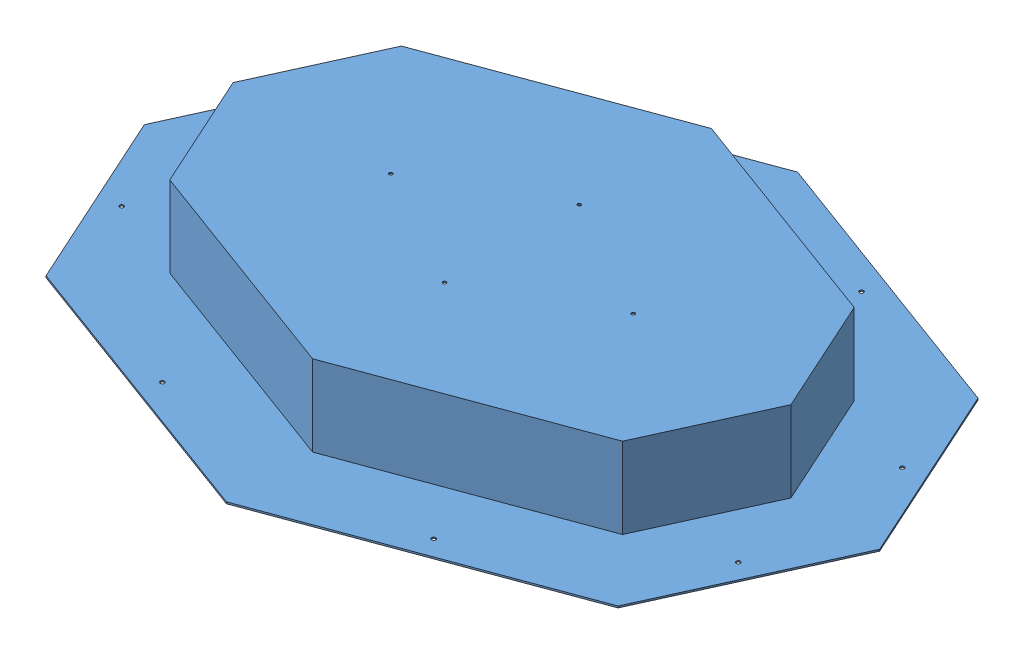
SolidWorks assembly SubAssembly_Lid, configuration Default. Lengths in mm.
Overall size (1707.58 155.58 1071.69).
23 component instances, 6 part files, 46 mates.
Components (placement in the parent):
- HullLid_Octagon-1: HullLid_Octagon [Default] at origin size (1707.58 155.58 1071.69)
- HullFoamTop_Octagon-1: HullFoamTop_Octagon [Default] at origin (suppressed, hidden)
- HullFoamTopPlate_Octagon-2: HullFoamTopPlate_Octagon [Default] at (0 305.9906 0) (suppressed, hidden)
- 90575A223_TYPE 316 STAINLESS STEEL FULLY THREADED STUD-2: 90575A223_TYPE 316 STAINLESS STEEL FULLY THREADED STUD [90575A223] at (-228.6 228.6 0) x (0 1 0) z (0 0 1) (suppressed, hidden)
- 90575A223_TYPE 316 STAINLESS STEEL FULLY THREADED STUD-5: 90575A223_TYPE 316 STAINLESS STEEL FULLY THREADED STUD [90575A223] at (0 228.6 127) x (0 1 0) z (-0.108702 0 -0.994074) (suppressed, hidden)
- 90575A223_TYPE 316 STAINLESS STEEL FULLY THREADED STUD-6: 90575A223_TYPE 316 STAINLESS STEEL FULLY THREADED STUD [90575A223] at (228.6 228.6 0) x (0 1 0) z (0.395734 0 0.918365) (suppressed, hidden)
- 90575A223_TYPE 316 STAINLESS STEEL FULLY THREADED STUD-7: 90575A223_TYPE 316 STAINLESS STEEL FULLY THREADED STUD [90575A223] at (0 228.6 -127) x (0 1 0) z (0.6 0 0.8) (suppressed, hidden)
- 90770A029_ALLOY 20 STAINLESS STEEL FLAT WASHER-1: 90770A029_ALLOY 20 STAINLESS STEEL FLAT WASHER [90770A029] at (-228.6 307.1813 0) x (0 1 0) z (0 0 1) (suppressed, hidden)
- 90770A029_ALLOY 20 STAINLESS STEEL FLAT WASHER-2: 90770A029_ALLOY 20 STAINLESS STEEL FLAT WASHER [90770A029] at (0 307.1813 -127) x (0 1 0) z (0.188455 0 0.982082) (suppressed, hidden)
- 90770A029_ALLOY 20 STAINLESS STEEL FLAT WASHER-3: 90770A029_ALLOY 20 STAINLESS STEEL FLAT WASHER [90770A029] at (228.6 307.1813 0) x (0 1 0) z (0.395734 0 0.918365) (suppressed, hidden)
- 90770A029_ALLOY 20 STAINLESS STEEL FLAT WASHER-4: 90770A029_ALLOY 20 STAINLESS STEEL FLAT WASHER [90770A029] at (0 307.1813 127) x (0 1 0) z (0.6 0 0.8) (suppressed, hidden)
- 90770A029_ALLOY 20 STAINLESS STEEL FLAT WASHER-5: 90770A029_ALLOY 20 STAINLESS STEEL FLAT WASHER [90770A029] at (-228.6 150.0188 0) x (0 -1 0) z (1 0 0) (suppressed, hidden)
- 90770A029_ALLOY 20 STAINLESS STEEL FLAT WASHER-6: 90770A029_ALLOY 20 STAINLESS STEEL FLAT WASHER [90770A029] at (0 150.0188 -127) x (0 -1 0) z (0.982082 0 -0.188455) (suppressed, hidden)
- 90770A029_ALLOY 20 STAINLESS STEEL FLAT WASHER-7: 90770A029_ALLOY 20 STAINLESS STEEL FLAT WASHER [90770A029] at (0 150.0188 127) x (0 -1 0) z (0.918365 0 -0.395734) (suppressed, hidden)
- 90770A029_ALLOY 20 STAINLESS STEEL FLAT WASHER-8: 90770A029_ALLOY 20 STAINLESS STEEL FLAT WASHER [90770A029] at (228.6 150.0188 0) x (0 -1 0) z (0.8 0 -0.6) (suppressed, hidden)
- 94819A043_ASTM F594 TYPE 316 STAINLESS STEEL HEX NUT-15: 94819A043_ASTM F594 TYPE 316 STAINLESS STEEL HEX NUT [94819A043] at (-228.6 311.7374 0) x (1 0 0) z (0 -1 0) (suppressed, hidden)
- 94819A043_ASTM F594 TYPE 316 STAINLESS STEEL HEX NUT-16: 94819A043_ASTM F594 TYPE 316 STAINLESS STEEL HEX NUT [94819A043] at (0 311.7374 -127) x (0.982082 0 -0.188455) z (0 -1 0) (suppressed, hidden)
- 94819A043_ASTM F594 TYPE 316 STAINLESS STEEL HEX NUT-17: 94819A043_ASTM F594 TYPE 316 STAINLESS STEEL HEX NUT [94819A043] at (0 311.7374 127) x (0.918365 0 -0.395734) z (0 -1 0) (suppressed, hidden)
- 94819A043_ASTM F594 TYPE 316 STAINLESS STEEL HEX NUT-18: 94819A043_ASTM F594 TYPE 316 STAINLESS STEEL HEX NUT [94819A043] at (228.6 311.7374 0) x (0.8 0 -0.6) z (0 -1 0) (suppressed, hidden)
- 94819A043_ASTM F594 TYPE 316 STAINLESS STEEL HEX NUT-19: 94819A043_ASTM F594 TYPE 316 STAINLESS STEEL HEX NUT [94819A043] at (228.6 145.4626 0) x (0 0 1) z (0 1 0) (suppressed, hidden)
- 94819A043_ASTM F594 TYPE 316 STAINLESS STEEL HEX NUT-20: 94819A043_ASTM F594 TYPE 316 STAINLESS STEEL HEX NUT [94819A043] at (0 145.4626 127) x (0 0 1) z (0 1 0) (suppressed, hidden)
- 94819A043_ASTM F594 TYPE 316 STAINLESS STEEL HEX NUT-21: 94819A043_ASTM F594 TYPE 316 STAINLESS STEEL HEX NUT [94819A043] at (-228.6 145.4626 0) x (0 0 1) z (0 1 0) (suppressed, hidden)
- 94819A043_ASTM F594 TYPE 316 STAINLESS STEEL HEX NUT-22: 94819A043_ASTM F594 TYPE 316 STAINLESS STEEL HEX NUT [94819A043] at (0 145.4626 -127) x (0 0 1) z (0 1 0) (suppressed, hidden)
Mates (geometry in assembly coordinates):
- Coincident1: coincident anti-aligned: plane of HullLid_Octagon-1 through (0 152.4 0) normal (0 1 0); plane of HullFoamTop_Octagon-1 through (0 152.4 0) normal (0 -1 0)
- Concentric1: concentric aligned: cylinder of HullLid_Octagon-1 through (0 -3.175 -127) axis (0 1 0) radius 3.175; cylinder of HullFoamTop_Octagon-1 through (0 0 -127) axis (0 1 0) radius 3.175
- Concentric2: concentric aligned: cylinder of HullLid_Octagon-1 through (228.6 -3.175 0) axis (0 1 0) radius 3.175; cylinder of HullFoamTop_Octagon-1 through (228.6 0 0) axis (0 1 0) radius 3.175
- Coincident2: coincident anti-aligned: plane of HullFoamTop_Octagon-1 through (0 304.8 0) normal (0 1 0); plane of HullFoamTopPlate_Octagon-2 through (0 304.8 0) normal (0 -1 0)
- Concentric3: concentric aligned: cylinder of HullFoamTop_Octagon-1 through (0 0 -127) axis (0 1 0) radius 3.175; cylinder of HullFoamTopPlate_Octagon-2 through (0 304.8 -127) axis (0 1 0) radius 3.175
- Concentric4: concentric aligned: cylinder of HullFoamTop_Octagon-1 through (228.6 0 0) axis (0 1 0) radius 3.175; cylinder of HullFoamTopPlate_Octagon-2 through (228.6 304.8 0) axis (0 1 0) radius 3.175
- Concentric5: concentric anti-aligned: cylinder of HullFoamTopPlate_Octagon-2 through (-228.6 304.8 0) axis (0 1 0) radius 3.175; circle of 90575A223_TYPE 316 STAINLESS STEEL FULLY THREADED STUD-2
- Width1: width aligned: plane of 90575A223_TYPE 316 STAINLESS STEEL FULLY THREADED STUD-2 through (-228.6 330.2 0) normal (0 1 0); plane of 90575A223_TYPE 316 STAINLESS STEEL FULLY THREADED STUD-2 through (-228.6 127 0) normal (0 -1 0); plane of HullFoamTopPlate_Octagon-2 through (0 307.1813 0) normal (0 1 0); plane of HullLid_Octagon-1 through (0 150.0188 0) normal (0 -1 0)
- Concentric6: concentric anti-aligned: circle of 90575A223_TYPE 316 STAINLESS STEEL FULLY THREADED STUD-5; cylinder of HullFoamTopPlate_Octagon-2 through (0 304.8 127) axis (0 1 0) radius 3.175
- Width2: width aligned: plane of 90575A223_TYPE 316 STAINLESS STEEL FULLY THREADED STUD-5 through (0 330.2 127) normal (0 1 0); plane of 90575A223_TYPE 316 STAINLESS STEEL FULLY THREADED STUD-5 through (0 127 127) normal (0 -1 0); plane of HullFoamTopPlate_Octagon-2 through (0 307.1813 0) normal (0 1 0); plane of HullLid_Octagon-1 through (0 150.0188 0) normal (0 -1 0)
- Width3: width aligned: plane of 90575A223_TYPE 316 STAINLESS STEEL FULLY THREADED STUD-6 through (228.6 330.2 0) normal (0 1 0); plane of 90575A223_TYPE 316 STAINLESS STEEL FULLY THREADED STUD-6 through (228.6 127 0) normal (0 -1 0); plane of HullFoamTopPlate_Octagon-2 through (0 307.1813 0) normal (0 1 0); plane of HullLid_Octagon-1 through (0 150.0188 0) normal (0 -1 0)
- Concentric7: concentric anti-aligned: circle of 90575A223_TYPE 316 STAINLESS STEEL FULLY THREADED STUD-6; cylinder of HullFoamTopPlate_Octagon-2 through (228.6 304.8 0) axis (0 1 0) radius 3.175
- Width4: width aligned: plane of 90575A223_TYPE 316 STAINLESS STEEL FULLY THREADED STUD-7 through (0 330.2 -127) normal (0 1 0); plane of 90575A223_TYPE 316 STAINLESS STEEL FULLY THREADED STUD-7 through (0 127 -127) normal (0 -1 0); plane of HullFoamTopPlate_Octagon-2 through (0 307.1813 0) normal (0 1 0); plane of HullLid_Octagon-1 through (0 150.0188 0) normal (0 -1 0)
- Concentric8: concentric anti-aligned: cylinder of HullFoamTopPlate_Octagon-2 through (0 304.8 -127) axis (0 1 0) radius 3.175; circle of 90575A223_TYPE 316 STAINLESS STEEL FULLY THREADED STUD-7
- Coincident17: coincident anti-aligned: plane of HullFoamTopPlate_Octagon-2 through (0 307.1813 0) normal (0 1 0); plane of 90770A029_ALLOY 20 STAINLESS STEEL FLAT WASHER-1 through (-228.6 307.1813 0) normal (0 -1 0)
- Concentric19: concentric anti-aligned: circle of 90575A223_TYPE 316 STAINLESS STEEL FULLY THREADED STUD-2; cylinder of 90770A029_ALLOY 20 STAINLESS STEEL FLAT WASHER-1 through (-228.6 308.9592 0) axis (0 -1 0) radius 3.302
- Coincident18: coincident anti-aligned: plane of HullFoamTopPlate_Octagon-2 through (0 307.1813 0) normal (0 1 0); plane of 90770A029_ALLOY 20 STAINLESS STEEL FLAT WASHER-2 through (0 307.1813 -127) normal (0 -1 0)
- Concentric20: concentric anti-aligned: circle of 90575A223_TYPE 316 STAINLESS STEEL FULLY THREADED STUD-7; cylinder of 90770A029_ALLOY 20 STAINLESS STEEL FLAT WASHER-2 through (0 308.9592 -127) axis (0 -1 0) radius 3.302
- Coincident19: coincident anti-aligned: plane of HullFoamTopPlate_Octagon-2 through (0 307.1813 0) normal (0 1 0); plane of 90770A029_ALLOY 20 STAINLESS STEEL FLAT WASHER-3 through (228.6 307.1813 0) normal (0 -1 0)
- Concentric21: concentric anti-aligned: circle of 90575A223_TYPE 316 STAINLESS STEEL FULLY THREADED STUD-6; cylinder of 90770A029_ALLOY 20 STAINLESS STEEL FLAT WASHER-3 through (228.6 308.9592 0) axis (0 -1 0) radius 3.302
- Coincident20: coincident anti-aligned: plane of HullFoamTopPlate_Octagon-2 through (0 307.1813 0) normal (0 1 0); plane of 90770A029_ALLOY 20 STAINLESS STEEL FLAT WASHER-4 through (0 307.1813 127) normal (0 -1 0)
- Concentric22: concentric anti-aligned: circle of 90575A223_TYPE 316 STAINLESS STEEL FULLY THREADED STUD-5; cylinder of 90770A029_ALLOY 20 STAINLESS STEEL FLAT WASHER-4 through (0 308.9592 127) axis (0 -1 0) radius 3.302
- Coincident21: coincident anti-aligned: plane of HullLid_Octagon-1 through (0 150.0188 0) normal (0 -1 0); plane of 90770A029_ALLOY 20 STAINLESS STEEL FLAT WASHER-5 through (-228.6 150.0188 0) normal (0 1 0)
- Concentric23: concentric anti-aligned: circle of 90575A223_TYPE 316 STAINLESS STEEL FULLY THREADED STUD-2; cylinder of 90770A029_ALLOY 20 STAINLESS STEEL FLAT WASHER-5 through (-228.6 148.2407 0) axis (0 1 0) radius 3.302
- Coincident22: coincident anti-aligned: plane of HullLid_Octagon-1 through (0 150.0188 0) normal (0 -1 0); plane of 90770A029_ALLOY 20 STAINLESS STEEL FLAT WASHER-6 through (0 150.0188 -127) normal (0 1 0)
- Concentric24: concentric anti-aligned: circle of 90575A223_TYPE 316 STAINLESS STEEL FULLY THREADED STUD-7; cylinder of 90770A029_ALLOY 20 STAINLESS STEEL FLAT WASHER-6 through (0 148.2407 -127) axis (0 1 0) radius 3.302
- Coincident23: coincident anti-aligned: plane of HullLid_Octagon-1 through (0 150.0188 0) normal (0 -1 0); plane of 90770A029_ALLOY 20 STAINLESS STEEL FLAT WASHER-7 through (0 150.0188 127) normal (0 1 0)
- Concentric25: concentric anti-aligned: circle of 90575A223_TYPE 316 STAINLESS STEEL FULLY THREADED STUD-5; cylinder of 90770A029_ALLOY 20 STAINLESS STEEL FLAT WASHER-7 through (0 148.2407 127) axis (0 1 0) radius 3.302
- Coincident24: coincident anti-aligned: plane of HullLid_Octagon-1 through (0 150.0188 0) normal (0 -1 0); plane of 90770A029_ALLOY 20 STAINLESS STEEL FLAT WASHER-8 through (228.6 150.0188 0) normal (0 1 0)
- Concentric26: concentric anti-aligned: circle of 90575A223_TYPE 316 STAINLESS STEEL FULLY THREADED STUD-6; cylinder of 90770A029_ALLOY 20 STAINLESS STEEL FLAT WASHER-8 through (228.6 148.2407 0) axis (0 1 0) radius 3.302
- Coincident26: coincident anti-aligned: plane of 90770A029_ALLOY 20 STAINLESS STEEL FLAT WASHER-1 through (-228.6 308.9592 0) normal (0 1 0); plane of 94819A043_ASTM F594 TYPE 316 STAINLESS STEEL HEX NUT-15 through (-234.1562 308.9592 3.2079) normal (0 -1 0)
- Concentric27: concentric aligned: circle of 94819A043_ASTM F594 TYPE 316 STAINLESS STEEL HEX NUT-15; circle of 90575A223_TYPE 316 STAINLESS STEEL FULLY THREADED STUD-2
- Coincident27: coincident anti-aligned: plane of 90770A029_ALLOY 20 STAINLESS STEEL FLAT WASHER-2 through (0 308.9592 -127) normal (0 1 0); plane of 94819A043_ASTM F594 TYPE 316 STAINLESS STEEL HEX NUT-16 through (-4.8521 308.9592 -122.8025) normal (0 -1 0)
- Concentric28: concentric aligned: circle of 90575A223_TYPE 316 STAINLESS STEEL FULLY THREADED STUD-7; circle of 94819A043_ASTM F594 TYPE 316 STAINLESS STEEL HEX NUT-16
- Coincident28: coincident anti-aligned: plane of 90770A029_ALLOY 20 STAINLESS STEEL FLAT WASHER-4 through (0 308.9592 127) normal (0 1 0); plane of 94819A043_ASTM F594 TYPE 316 STAINLESS STEEL HEX NUT-17 through (-3.8332 308.9592 132.1448) normal (0 -1 0)
- Concentric29: concentric aligned: circle of 90575A223_TYPE 316 STAINLESS STEEL FULLY THREADED STUD-5; circle of 94819A043_ASTM F594 TYPE 316 STAINLESS STEEL HEX NUT-17
- Coincident29: coincident anti-aligned: plane of 90770A029_ALLOY 20 STAINLESS STEEL FLAT WASHER-3 through (228.6 308.9592 0) normal (0 1 0); plane of 94819A043_ASTM F594 TYPE 316 STAINLESS STEEL HEX NUT-18 through (226.0797 308.9592 5.9001) normal (0 -1 0)
- Concentric30: concentric aligned: circle of 90575A223_TYPE 316 STAINLESS STEEL FULLY THREADED STUD-6; circle of 94819A043_ASTM F594 TYPE 316 STAINLESS STEEL HEX NUT-18
- Coincident30: coincident anti-aligned: plane of 90770A029_ALLOY 20 STAINLESS STEEL FLAT WASHER-8 through (228.6 148.2407 0) normal (0 -1 0); plane of 94819A043_ASTM F594 TYPE 316 STAINLESS STEEL HEX NUT-19 through (231.8079 148.2407 -5.5563) normal (0 1 0)
- Concentric31: concentric aligned: circle of 90575A223_TYPE 316 STAINLESS STEEL FULLY THREADED STUD-6; circle of 94819A043_ASTM F594 TYPE 316 STAINLESS STEEL HEX NUT-19
- Coincident31: coincident anti-aligned: plane of 90770A029_ALLOY 20 STAINLESS STEEL FLAT WASHER-7 through (0 148.2407 127) normal (0 -1 0); plane of 94819A043_ASTM F594 TYPE 316 STAINLESS STEEL HEX NUT-20 through (3.2079 148.2407 121.4438) normal (0 1 0)
- Concentric32: concentric aligned: circle of 90575A223_TYPE 316 STAINLESS STEEL FULLY THREADED STUD-5; circle of 94819A043_ASTM F594 TYPE 316 STAINLESS STEEL HEX NUT-20
- Coincident32: coincident anti-aligned: plane of 90770A029_ALLOY 20 STAINLESS STEEL FLAT WASHER-5 through (-228.6 148.2407 0) normal (0 -1 0); plane of 94819A043_ASTM F594 TYPE 316 STAINLESS STEEL HEX NUT-21 through (-225.3921 148.2407 -5.5563) normal (0 1 0)
- Concentric33: concentric aligned: circle of 90575A223_TYPE 316 STAINLESS STEEL FULLY THREADED STUD-2; circle of 94819A043_ASTM F594 TYPE 316 STAINLESS STEEL HEX NUT-21
- Coincident33: coincident anti-aligned: plane of 90770A029_ALLOY 20 STAINLESS STEEL FLAT WASHER-6 through (0 148.2407 -127) normal (0 -1 0); plane of 94819A043_ASTM F594 TYPE 316 STAINLESS STEEL HEX NUT-22 through (3.2079 148.2407 -132.5562) normal (0 1 0)
- Concentric34: concentric aligned: circle of 90575A223_TYPE 316 STAINLESS STEEL FULLY THREADED STUD-7; circle of 94819A043_ASTM F594 TYPE 316 STAINLESS STEEL HEX NUT-22
